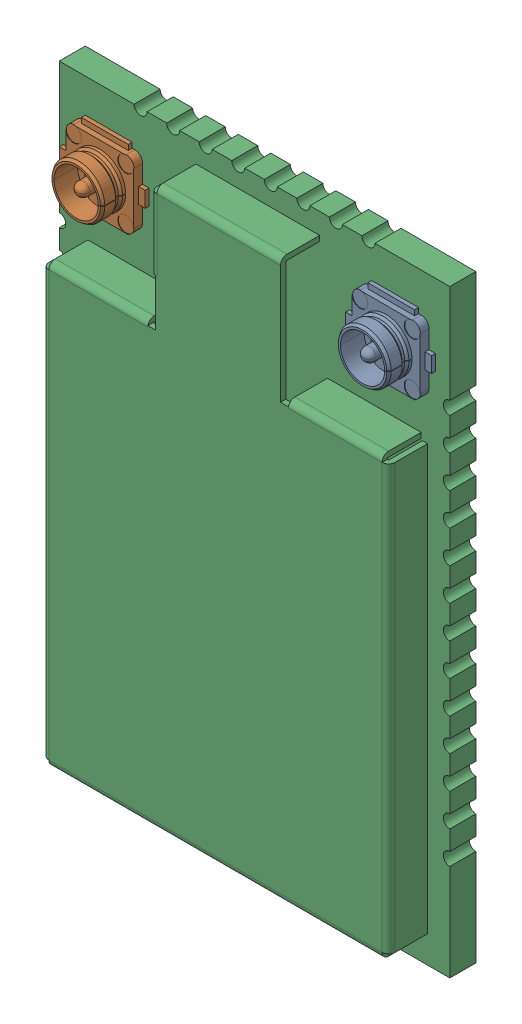
SolidWorks assembly RAK4600, configuration Predeterminado. Lengths in mm.
Overall size (15 23 2.5).
4 component instances, 2 part files, 0 mates.
Components (placement in the parent):
- PWB-RAK4600-1: PWB-RAK4600 [Predeterminado] at (15.223 9.3639 2.5146) x (1 0 0) z (0 -1 0) size (15 2.5 23)
  - IPEX-FEMALE-1: IPEX-FEMALE [Predeterminado] at (12.05 -1.5 -19.4) x (0 0 -1) z (1 0 0) size (3 1.25 3.1)
  - IPEX-FEMALE-2: IPEX-FEMALE [Predeterminado] at (1.05 -1.5 -19.4) x (0 0 -1) z (1 0 0) size (3 1.25 3.1)
  - 6310C00F_RAK4600-1: 6310C00F_RAK4600 [Predeterminado] at origin size (15 2.5 23)
